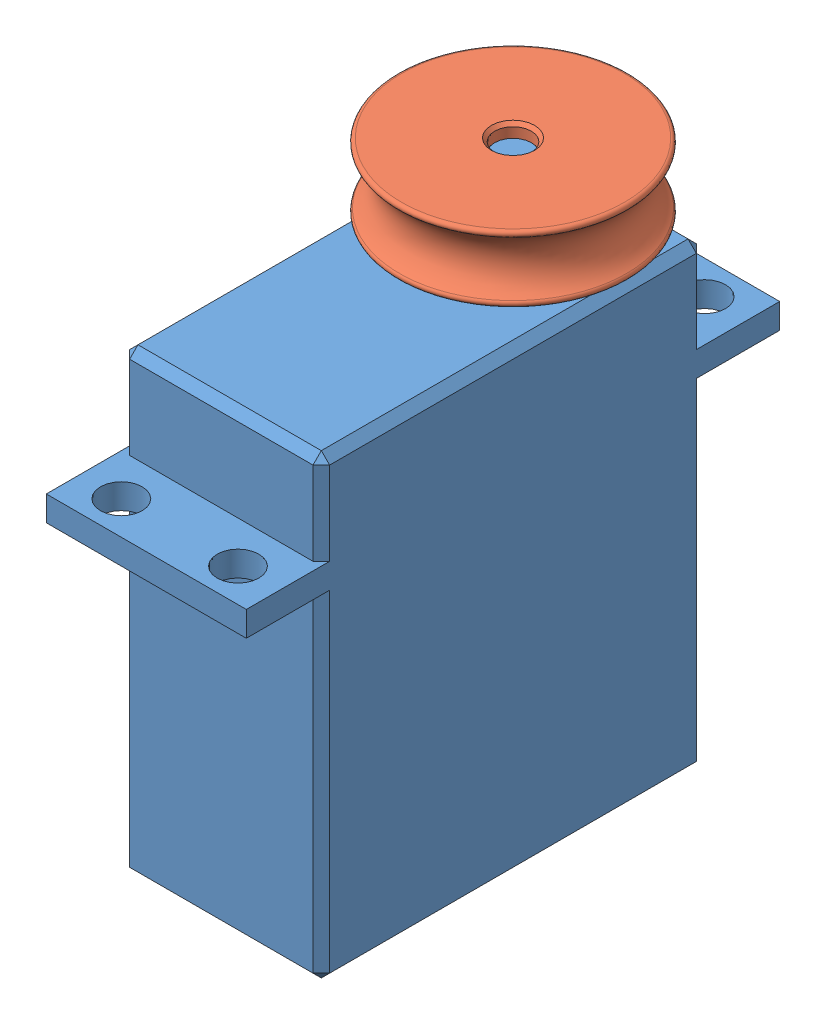
SolidWorks assembly ServoAssem, configuration Default. Lengths in mm.
Overall size (13.78 32.4 32).
2 component instances, 2 part files, 3 mates.
Components (placement in the parent):
- AGFRC Micro Servo-1: AGFRC Micro Servo [Default] at origin size (12 31.6 32)
- Pulley-1: Pulley [Default] at (0 28.4 5.5) x (1 0 0) z (0 -1 0) size (13.78 13.78 4)
Mates (geometry in assembly coordinates):
- Concentric1: concentric aligned: cylinder of AGFRC Micro Servo-1 through (0 31.6 5.5) axis (0 -1 0) radius 2.45; cylinder of Pulley-1 through (0 28.4 5.5) axis (0 -1 0) radius 2.55
- Coincident1: coincident anti-aligned: plane of AGFRC Micro Servo-1 through (0 28.4 5.5) normal (0 1 0); plane of Pulley-1 through (7.55 28.4 5.5) normal (0 -1 0)
- Coincident2: coincident aligned: plane of Pulley-1 through (0 28.4 5.5) normal (1 0 0)
